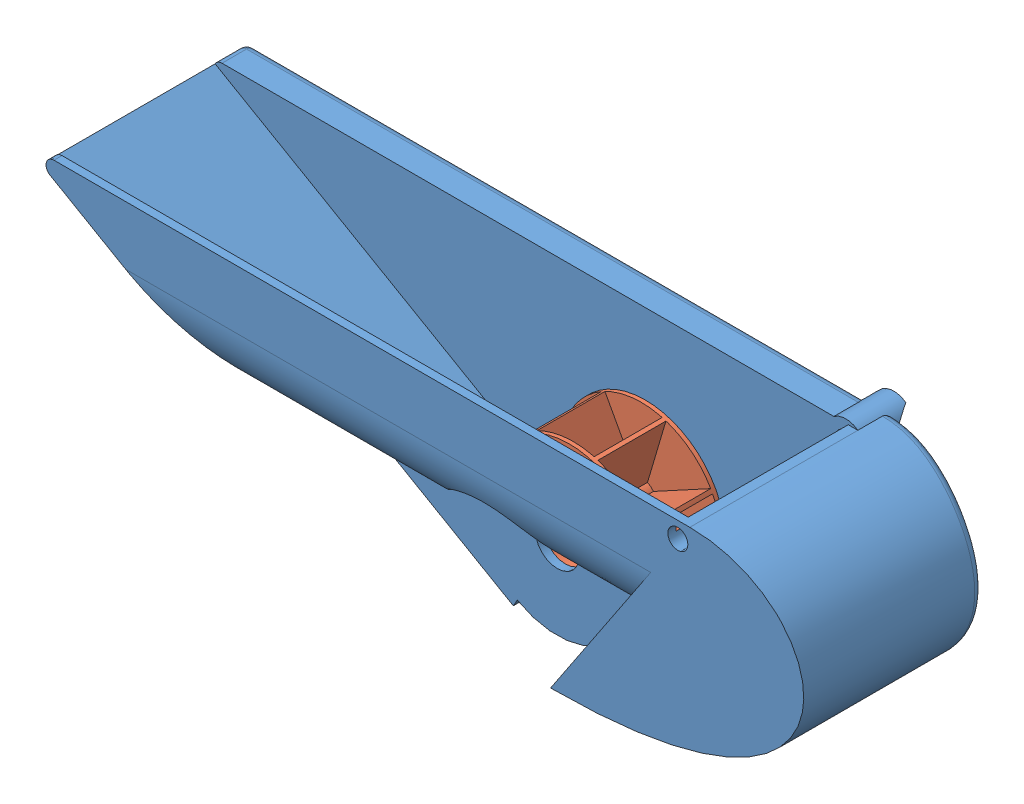
SolidWorks assembly Dropper, configuration Default. Lengths in mm.
Overall size (247.92 92.61 74.32).
2 component instances, 2 part files, 2 mates.
Components (placement in the parent):
- Airframe Mount-1: Airframe Mount [Default] at (108.9494 127.738 161.7903) size (247.92 83.57 74.32)
- Variable Speed Release-1: Variable Speed Release [Default] at (108.9494 127.738 161.7903) x (0.477276 -0.878754 0) z (-0.878754 -0.477276 0) size (50.8 24.13 50.8)
Mates (geometry in assembly coordinates):
- Coincident1: coincident anti-aligned: plane of Airframe Mount-1 through (108.9494 127.738 161.7903) normal (0 0 1); plane of Variable Speed Release-1 through (108.9494 127.738 161.7903) normal (0 0 -1)
- Concentric1: concentric anti-aligned: cylinder of Airframe Mount-1 through (108.9494 127.738 164.3303) axis (0 0 1) radius 6.985; cylinder of Variable Speed Release-1 through (108.9494 127.738 184.6503) axis (0 0 -1) radius 11.1125
